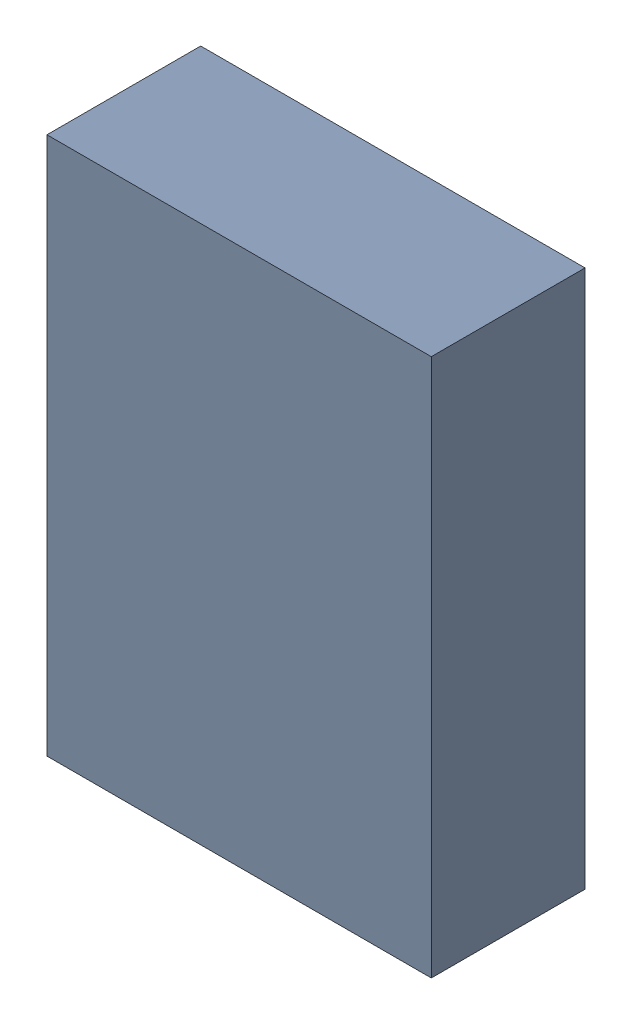
SolidWorks assembly Kanaloa_v2.0.0_Loko_9, configuration Default. Lengths in mm.
Overall size (2.5 3.5 1).
2 component instances, 1 part files, 0 mates.
Components (placement in the parent):
- 378153280_1-1: 378153280_1 [Default] at (67.568 74.8538 0) size (2.5 3.5 1)
  - Extruded_33-1: Extruded_33 [Default] at origin size (2.5 3.5 1)
